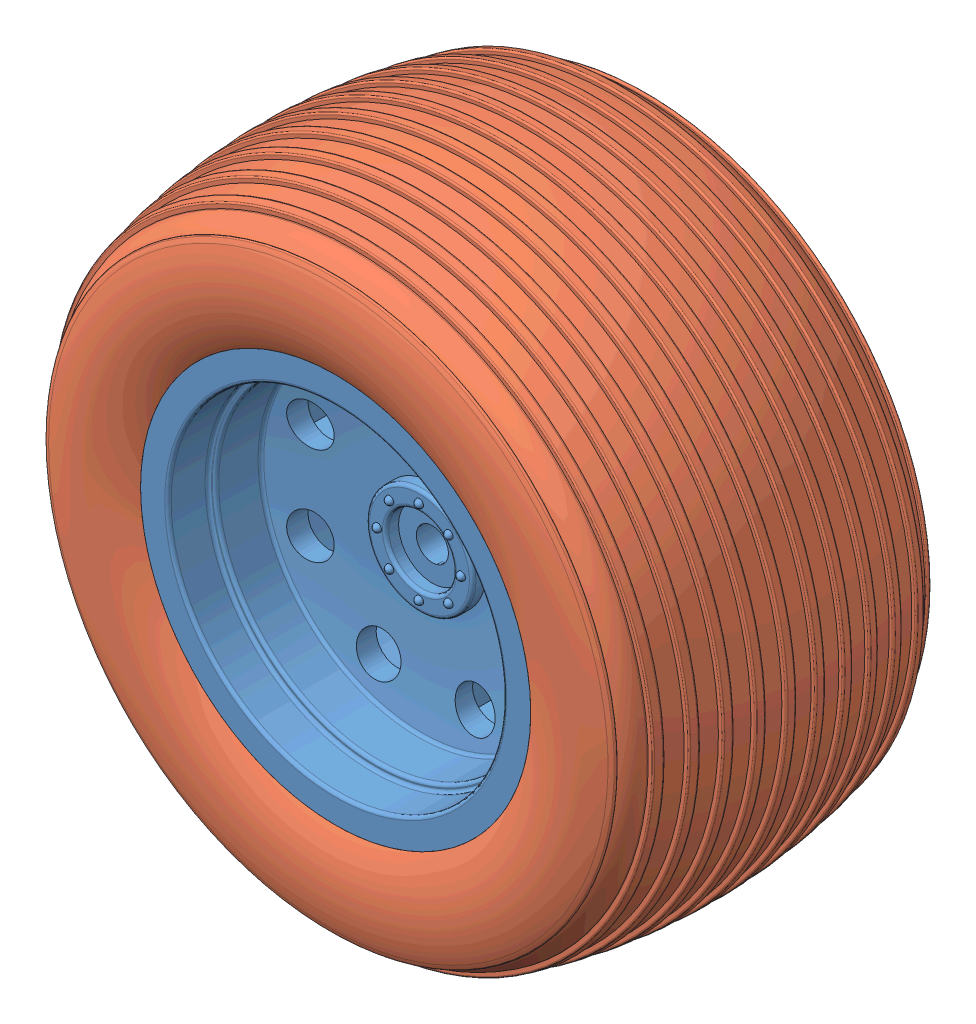
SolidWorks assembly wheel(front wheel), configuration Default. Lengths in mm.
Overall size (100.29 100.29 52.19).
3 component instances, 3 part files, 3 mates.
Components (placement in the parent):
- 5576-1: 5576 [Default] at origin size (61.47 61.47 48.01)
- Part1^wheel-1: Part1^wheel [Default] at origin size (100.29 100.29 52.19)
- Part2^wheel(front wheel)-1: Part2^wheel(front wheel) [Default] at origin (suppressed, hidden, virtual)
Mates (geometry in assembly coordinates):
- Coincident1: coordinate: point of 5576-1
- Coincident2: coordinate: point of 5576-1; point of Part1^wheel-1
- Coincident3: coordinate: unknown of Part2^wheel(front wheel)-1
